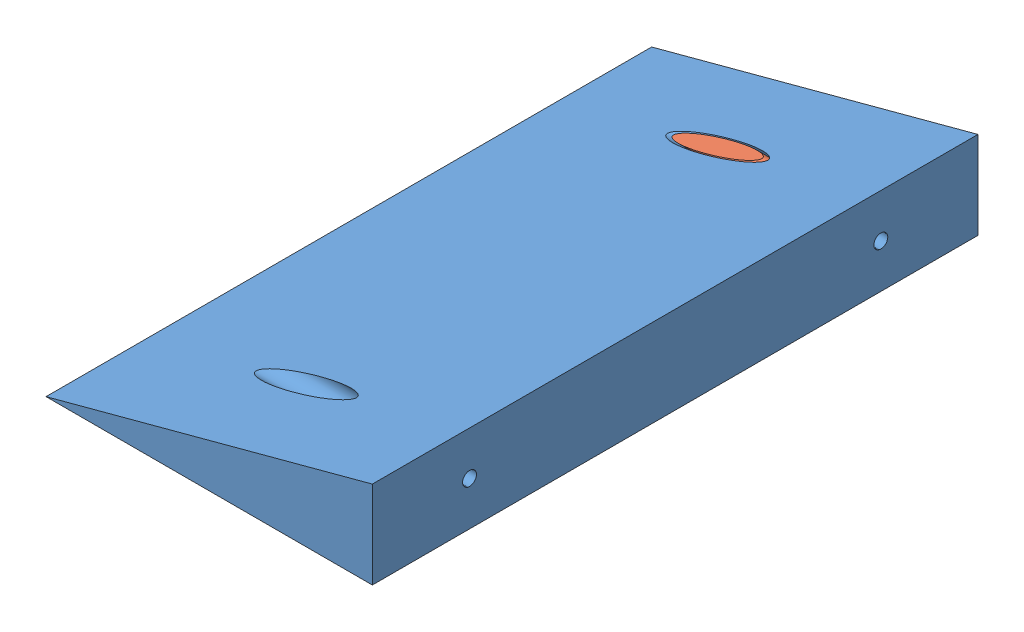
SolidWorks assembly Montagem Rampa, configuration Default. Lengths in mm.
Overall size (100.77 27 187).
2 component instances, 2 part files, 1 mates.
Components (placement in the parent):
- rampa_interna-1: rampa_interna [Default] at (-127.2244 -8.1204 -3.434) size (100.77 27 187)
- Peça3^Montagem Rampa-1: Peça3^Montagem Rampa [Default] at (-193.0034 -22.2876 44.3642) x (0 -0.98895 0.148247) z (1 0 0) size (7.3 7.3 36) (virtual)
Mates (geometry in assembly coordinates):
- Concêntrico1: concentric aligned: cylinder of rampa_interna-1 through (-152.2244 5.3796 26.566) axis (-1 0 0) radius 4.15; cylinder of Peça3^Montagem Rampa-1 through (-157.0034 5.3796 26.566) axis (-1 0 0) radius 3.65
